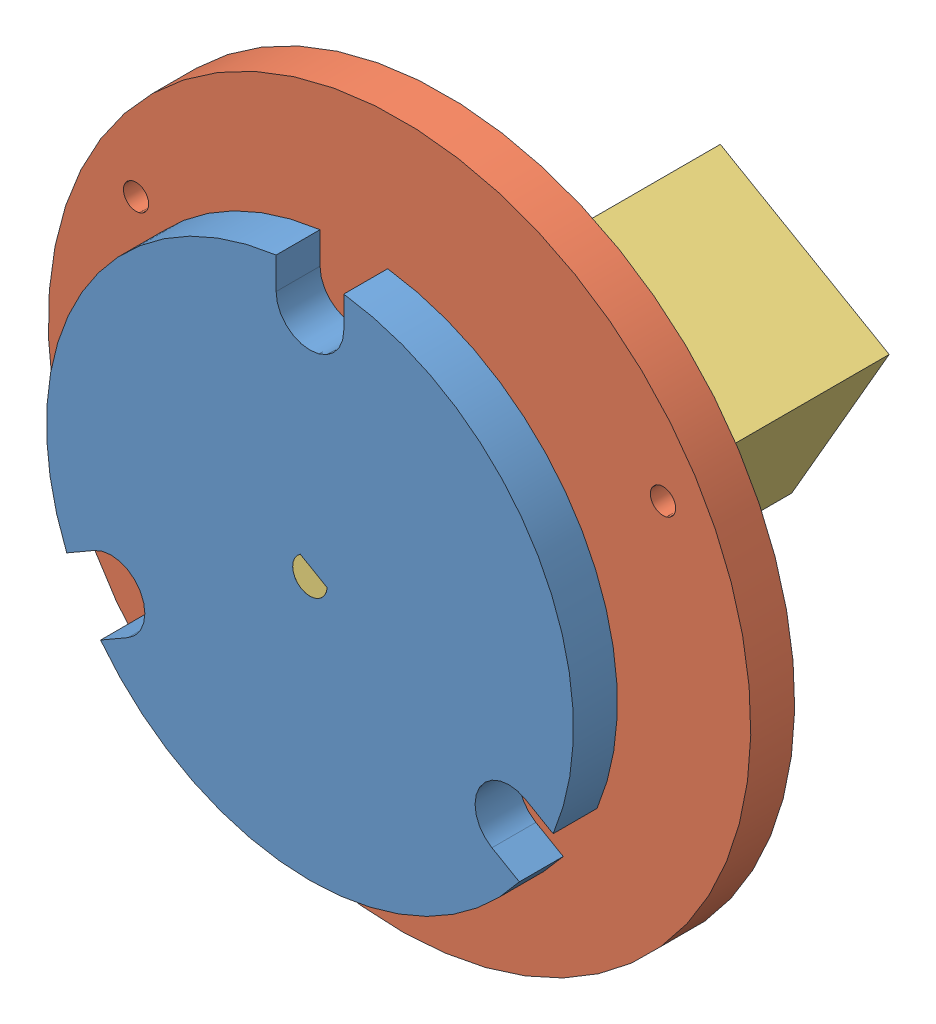
SolidWorks assembly motor_disk_assembly, configuration Default. Lengths in mm.
Overall size (138.79 138.79 64.5).
7 component instances, 4 part files, 7 mates.
Components (placement in the parent):
- disk-1: disk [Default] at (-26.4287 6.231 6.6448) size (76.2 75.77 6.35)
- motor_key-1: motor_key [Default] at (-26.4287 6.231 -6.3092) x (-0.5 -0.866025 0) z (0 0 1) size (101.6 101.6 6.35)
- nema11-1: nema11 [Default] at (-31.5896 25.492 -51.5052) x (-0.5 -0.866025 0) z (0 0 1) size (28.2 28.2 64.5)
- 2.5mm_screw-1: 2.5mm_screw [91292A009] at (-42.138 2.0217 -7.4592) x (-0.991496 0.130134 0) z (0 0 -1) size (4.5 4.5 8.01)
- 2.5mm_screw-2: 2.5mm_screw [91292A009] at (-22.2194 -9.4783 -7.4592) x (-0.130134 -0.991496 0) z (0 0 -1) size (4.5 4.5 8.01)
- 2.5mm_screw-3: 2.5mm_screw [91292A009] at (-10.7194 10.4403 -7.4592) x (0.991496 -0.130134 0) z (0 0 -1) size (4.5 4.5 8.01)
- 2.5mm_screw-4: 2.5mm_screw [91292A009] at (-30.638 21.9403 -7.4592) x (0.130134 0.991496 0) z (0 0 -1) size (4.5 4.5 8.01)
Mates (geometry in assembly coordinates):
- Concentric2: concentric: circle of assembly; circle of assembly; circle of motor_key-1; circle of nema11-1
- Concentric3: concentric: circle of assembly; circle of assembly; circle of motor_key-1; circle of nema11-1
- Concentric4: concentric: circle of assembly; circle of assembly; circle of motor_key-1; circle of 2.5mm_screw-1
- Coincident4: coincident: plane of assembly; plane of assembly; plane of motor_key-1 through (-42.813 0.8526 -2.4592) normal (0 0 1); plane of 2.5mm_screw-1 through (-42.138 2.0217 -2.4592) normal (0 0 -1)
- Distance1: distance = 6.604 mm: plane of assembly; plane of assembly; plane of disk-1 through (-26.4287 6.231 6.6448) normal (0 0 -1); plane of motor_key-1 through (-26.4287 6.231 0.0408) normal (0 0 1)
- Parallel1: parallel: plane of assembly; plane of assembly; plane of disk-1 through (-0.1123 -14.6087 6.6448) normal (0.5 0.866025 0); plane of nema11-1 through (-23.9353 6.0497 -2.0052) normal (0.5 0.866025 0)
- Coincident6: coincident: circle of assembly; circle of assembly; circle of disk-1; circle of nema11-1
